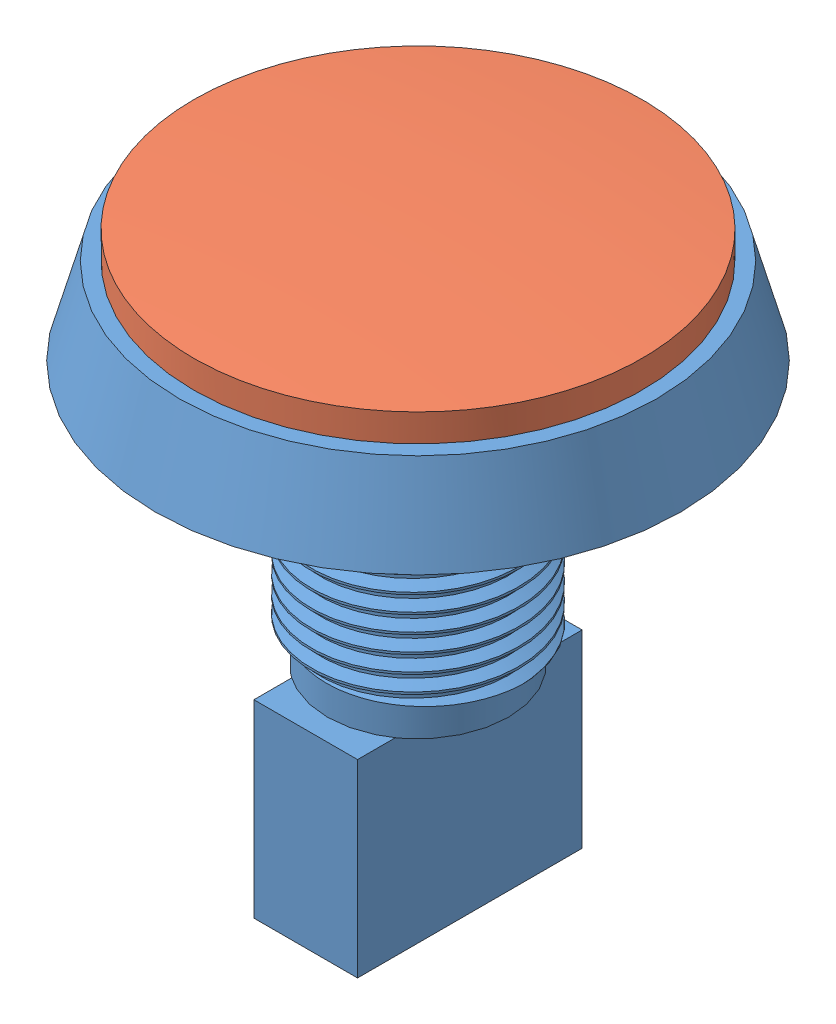
SolidWorks assembly arcade_button_60mm_blue, configuration Default. Lengths in mm.
Overall size (60.8 66.8 60.8).
2 component instances, 2 part files, 2 mates.
Components (placement in the parent):
- arcade_button_60mm-1: arcade_button_60mm [Default] at origin size (60.8 62.4 60.8)
- arcade_button_60mm_blue-1: arcade_button_60mm_blue [Default] at (0 10 0) size (51.9 4.4 51.9)
Mates (geometry in assembly coordinates):
- Coincident11: coincident anti-aligned: plane of arcade_button_60mm-1 through (-27.65 10 0) normal (0 1 0); plane of arcade_button_60mm_blue-1 through (0 10 0) normal (0 -1 0)
- Concentric11: concentric aligned: line of arcade_button_60mm-1 through (10 0 0) axis (0 0 1); line of arcade_button_60mm_blue-1 through (4.4 0 10) axis (0 0 1)
